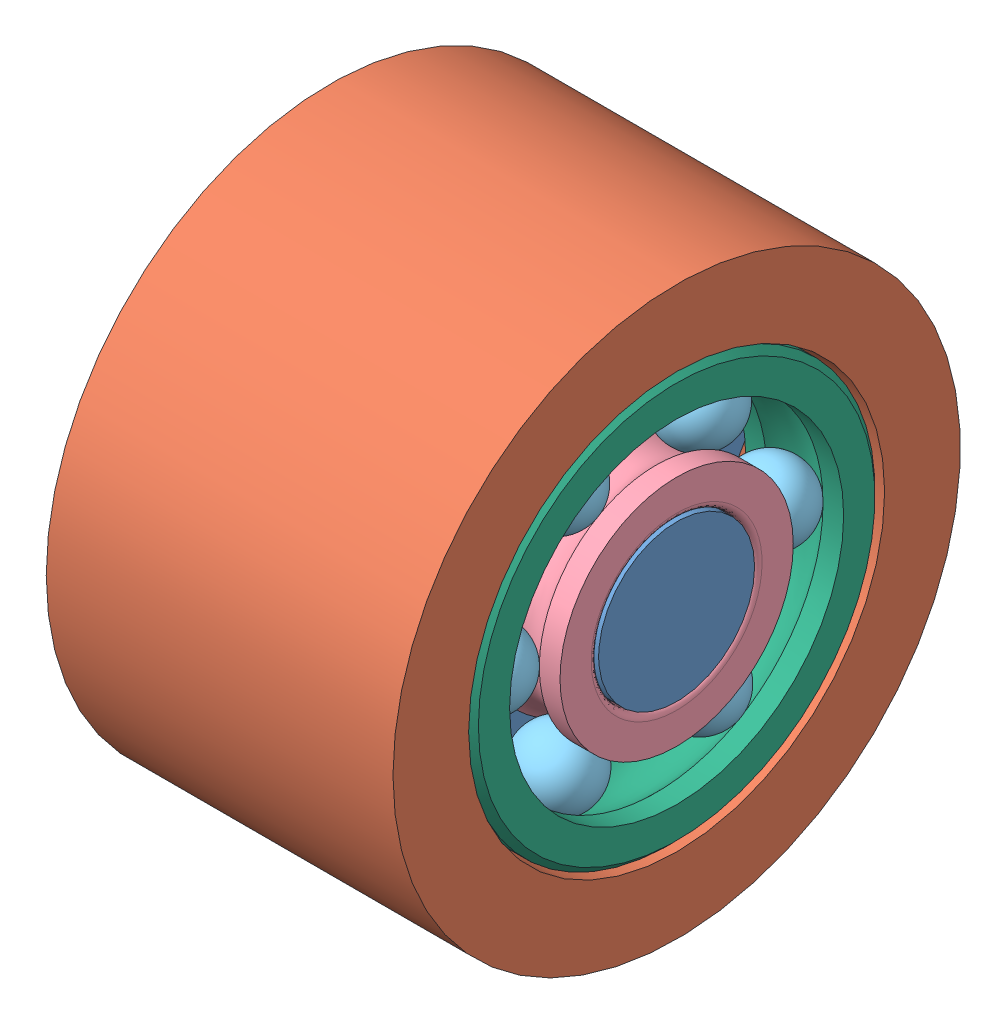
SolidWorks assembly Assem1, configuration Default. Lengths in mm.
Overall size (137.3 204.01 387.65).
28 component instances, 7 part files, 7 mates.
Components (placement in the parent):
- Assem3^Assem1-1: Assem3^Assem1 [Default] at origin (virtual)
- MAIN2-1: MAIN2 [Default] at (167.7012 50.2758 208.2824) x (0 0 1) z (-1 0 0) size (109.58 108.94 110)
- bapu-2: bapu [Default] at (167.7012 13.4459 208.2824) size (110 180 180)
- rod-2: rod [Default] at (167.7012 39.8024 166.3706) x (0 0 -1) z (1 0 0) size (13 13 48)
- rod-3: rod [Default] at (167.7012 62.9209 210.1518) x (0 0.866025 -0.5) z (1 0 0) size (13 13 48)
- rod-4: rod [Default] at (167.7012 36.5645 252.0637) x (0 0.866025 0.5) z (1 0 0) size (13 13 48)
- rod-5: rod [Default] at (167.7012 -12.9105 250.1943) x (0 0 1) z (1 0 0) size (13 13 48)
- rod-6: rod [Default] at (167.7012 -36.029 206.413) x (0 -0.866025 0.5) z (1 0 0) size (13 13 48)
- rod-7: rod [Default] at (167.7012 -9.6726 164.5012) x (0 -0.866025 -0.5) z (1 0 0) size (13 13 48)
- Part1^Assem1-1: Part1^Assem1 [Default] at origin (virtual)
- Assem4-1: Assem4 [Default] at (208.3488 -32.2497 141.1086) size (31 130 130)
  - inner ring-1: inner ring [Default] at (-1.1476 45.6956 67.1738) x (1 0 0) z (0 0.999989 0.004731) size (31 74 74)
  - ball-1: ball [Default] at (-1.1476 45.4827 112.1733) x (1 0 0) z (0 0.999989 0.004731) size (24 24 24)
  - outer ring-1: outer ring [Default] at (-1.1476 45.6956 67.1738) size (31 130 130)
  - ball-2: ball [Default] at (-1.1476 84.5599 89.8579) x (1 0 0) z (0 0.504091 -0.86365) size (24 24 24)
  - ball-3: ball [Default] at (-1.1476 84.7728 44.8584) x (1 0 0) z (0 -0.495897 -0.868381) size (24 24 24)
  - ball-4: ball [Default] at (-1.1476 45.9085 22.1743) x (1 0 0) z (0 -0.999989 -0.004731) size (24 24 24)
  - ball-5: ball [Default] at (-1.1476 6.8313 44.4897) x (1 0 0) z (0 -0.504091 0.86365) size (24 24 24)
  - ball-6: ball [Default] at (-1.1476 6.6185 89.4892) x (1 0 0) z (0 0.495897 0.868381) size (24 24 24)
- Assem4-2: Assem4 [Default] at (129.3488 -32.2497 141.1086) size (31 130 130)
  - inner ring-1: inner ring [Default] at (-1.1476 45.6956 67.1738) x (1 0 0) z (0 0.999989 0.004731) size (31 74 74)
  - ball-1: ball [Default] at (-1.1476 45.4827 112.1733) x (1 0 0) z (0 0.999989 0.004731) size (24 24 24)
  - outer ring-1: outer ring [Default] at (-1.1476 45.6956 67.1738) size (31 130 130)
  - ball-2: ball [Default] at (-1.1476 84.5599 89.8579) x (1 0 0) z (0 0.504091 -0.86365) size (24 24 24)
  - ball-3: ball [Default] at (-1.1476 84.7728 44.8584) x (1 0 0) z (0 -0.495897 -0.868381) size (24 24 24)
  - ball-4: ball [Default] at (-1.1476 45.9085 22.1743) x (1 0 0) z (0 -0.999989 -0.004731) size (24 24 24)
  - ball-5: ball [Default] at (-1.1476 6.8313 44.4897) x (1 0 0) z (0 -0.504091 0.86365) size (24 24 24)
  - ball-6: ball [Default] at (-1.1476 6.6185 89.4892) x (1 0 0) z (0 0.495897 0.868381) size (24 24 24)
Mates (geometry in assembly coordinates):
- Coincident3: coincident anti-aligned: plane of MAIN2-1 through (167.7012 50.2758 208.2824) normal (-1 0 0); plane of rod-2 through (167.7012 39.8024 166.3706) normal (1 0 0)
- Width3: width aligned: plane of MAIN2-1 through (143.7012 50.2758 208.2824) normal (-1 0 0); plane of MAIN2-1 through (191.7012 50.2758 208.2824) normal (1 0 0); plane of bapu-2 through (112.7012 13.4459 208.2824) normal (-1 0 0); plane of bapu-2 through (222.7012 13.4459 208.2824) normal (1 0 0)
- Concentric3: concentric aligned: cylinder of MAIN2-1; cylinder of bapu-2 through (158.2568 13.4459 208.2824) axis (-1 0 0) radius 90
- Concentric4: concentric aligned: cylinder of bapu-2 through (158.2568 13.4459 208.2824) axis (-1 0 0) radius 66; cylinder of Assem4-1/outer ring-1 through (159.8358 13.4459 208.2824) axis (-1 0 0) radius 65
- Coincident7: coincident aligned: plane of bapu-2 through (222.7012 13.4459 208.2824) normal (1 0 0); plane of Assem4-1/outer ring-1 through (222.7012 78.4459 208.2824) normal (1 0 0)
- Concentric6: concentric aligned: cylinder of bapu-2 through (158.2568 13.4459 208.2824) axis (-1 0 0) radius 66; cylinder of Assem4-2/outer ring-1 through (80.8358 13.4459 208.2824) axis (-1 0 0) radius 65
- Coincident8: coincident aligned: plane of bapu-2 through (112.7012 13.4459 208.2824) normal (-1 0 0); plane of Assem4-2/outer ring-1 through (112.7012 78.4459 208.2824) normal (-1 0 0)
